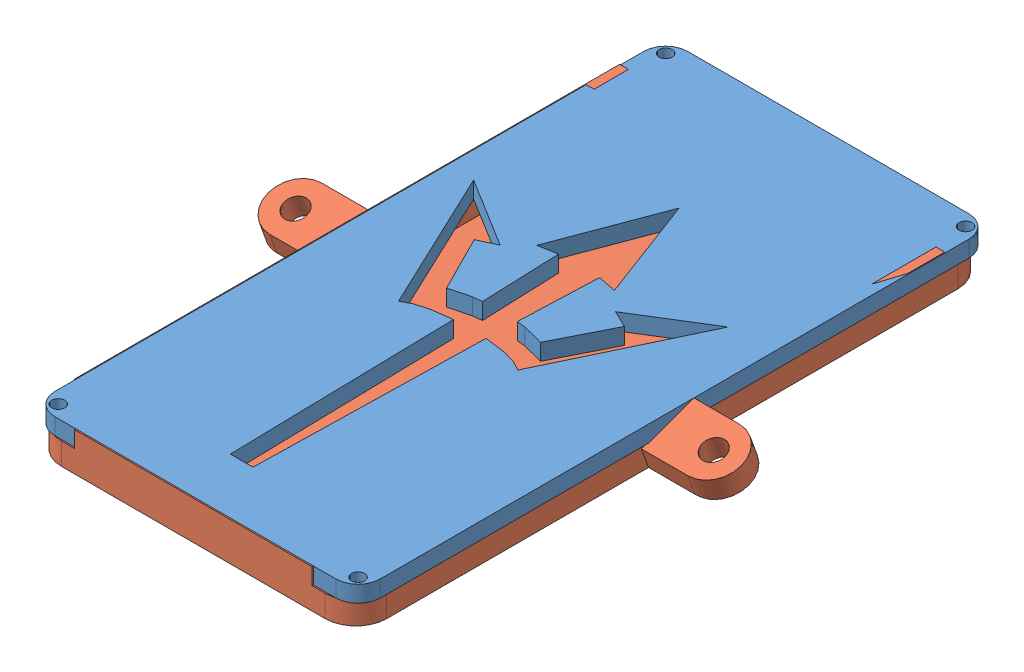
SolidWorks assembly Brakelight, configuration Default. Lengths in mm.
Overall size (136.73 11.11 183.26).
2 component instances, 2 part files, 1 mates.
Components (placement in the parent):
- Brake Light Cover-1: Brake Light Cover [Default] at (4.9882 65.3396 205.7351) size (93.98 4.76 182.88)
- NewBrakeLight-1: NewBrakeLight [Default] at (7.287 58.9896 203.5748) size (136.73 11.11 182.88)
Mates (geometry in assembly coordinates):
- Coincident1: coincident anti-aligned: plane of Brake Light Cover-1 through (4.9882 65.3396 205.7351) normal (0 -1 0); plane of NewBrakeLight-1 through (7.287 65.3396 203.5748) normal (0 1 0)
